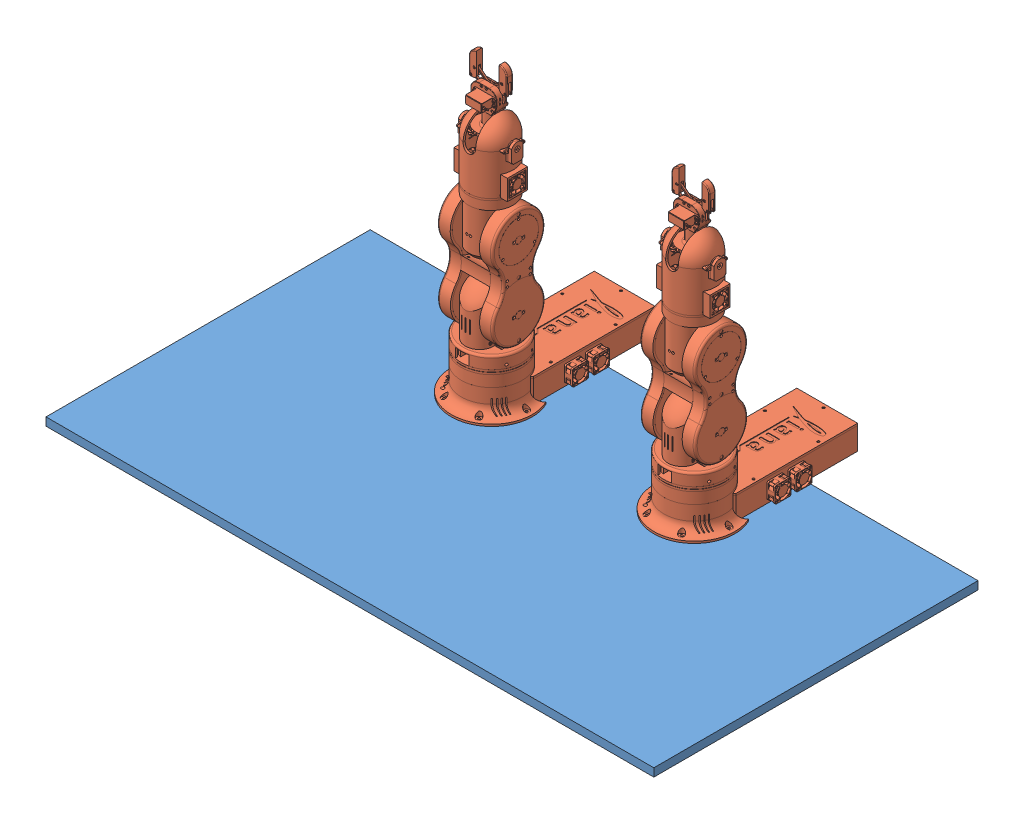
SolidWorks assembly mesa1, configuration Predeterminado. Lengths in mm.
Overall size (1500 741.22 927.94).
3 component instances, 2 part files, 6 mates.
Components (placement in the parent):
- mesa-1: mesa [Predeterminado] at origin size (1500 20 800)
- URDF-1: URDF [Predeterminado] at (-250 20 -200) x (0 0 1) z (0 1 0) size (427.94 200 721.22)
- URDF-2: URDF [Predeterminado] at (250 20 -200) x (0 0 1) z (0 1 0) size (427.94 200 721.22)
Mates (geometry in assembly coordinates):
- Distancia1: distance = 500 mm: cylinder of URDF-1 through (-250 98.0387 -200) axis (0 1 0) radius 100; cylinder of URDF-2 through (250 98.0387 -200) axis (0 1 0) radius 100
- Coincidente1: coincident anti-aligned: plane of mesa-1 through (0 20 0) normal (0 1 0); plane of URDF-2 through (250 20 -192.2259) normal (0 -1 0)
- Coincidente3: coincident aligned: line of URDF-1 through (-175 20 -520.1696) axis (-1 0 0); line of URDF-2 through (325 20 -520.1696) axis (-1 0 0)
- Coincidente12: coincident: point of mesa-1; unknown of URDF-1
- Paralelo1: parallel aligned: plane of mesa-1 through (-750 20 400) normal (-1 0 0); plane of URDF-1 through (-325 75 -520.1696) normal (-1 0 0)
- Distancia2: distance = 500 mm: unknown of URDF-1; plane of mesa-1 through (750 20 400) normal (0 0 1)
